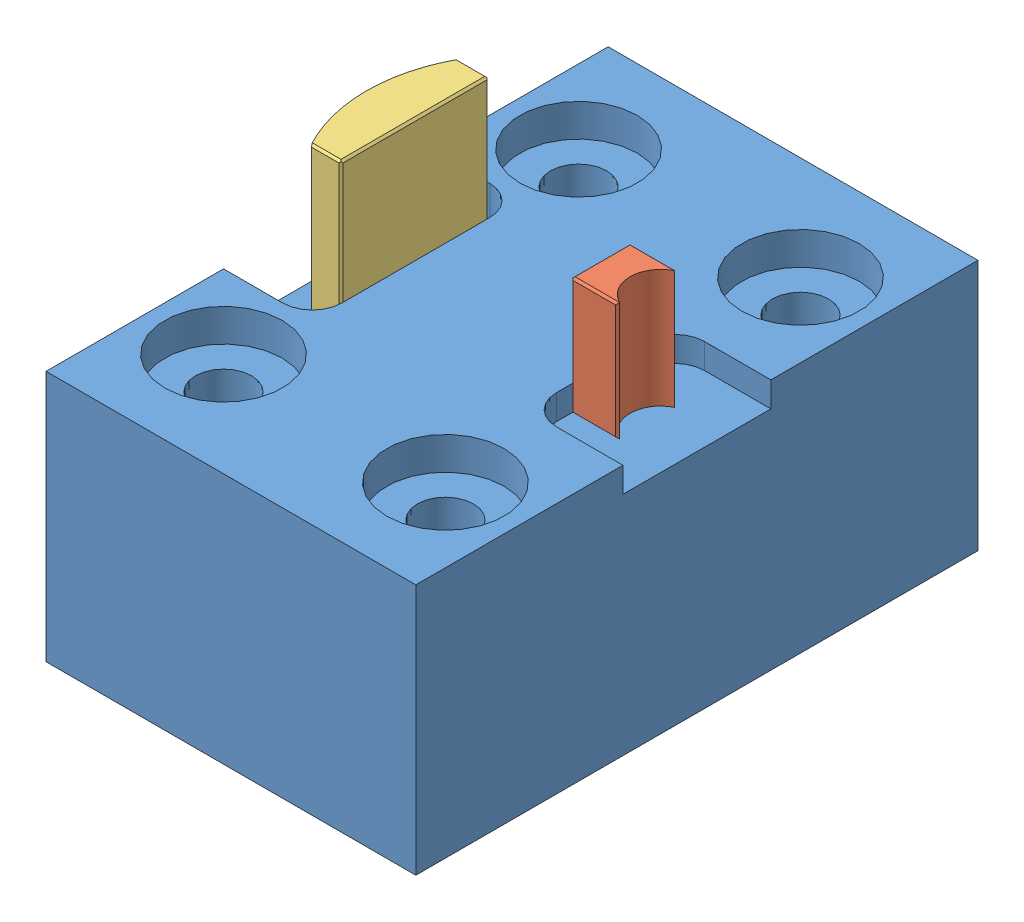
SolidWorks assembly telescope_assem, configuration Default. Lengths in mm.
Overall size (25 25.3 38).
3 component instances, 3 part files, 6 mates.
Components (placement in the parent):
- telescope_stand-1: telescope_stand [Default] at (18495.2515 8.1592 11328.0159) size (25 17 38)
- cyl_lens_concave-2: cyl_lens_concave [Default] at (21.3841 27.4592 29.848) x (0 1 0) z (1 0 0) size (8 4 3.16)
- cylindricalconvex_LJ1960L1-B-Solidworks-1: cylindricalconvex_LJ1960L1-B-Solidworks [Default] at (5.6598 27.4592 29.8856) x (0 1 0) z (-1 0 0) size (12 10 3.29)
Mates (geometry in assembly coordinates):
- Coincident2: coincident: plane of telescope_stand-1 through (18495.2515 23.4592 11328.0159) normal (0 1 0); plane of cyl_lens_concave-1 through (23.8748 28.4592 28.05) normal (0 -1 0)
- Coincident3: coincident anti-aligned: plane of telescope_stand-1 through (19.8048 -3.7676 11328.0159) normal (1 0 0); plane of cyl_lens_concave-1 through (19.8048 36.4592 30.05) normal (-1 0 0)
- Coincident6: coincident anti-aligned: plane of telescope_stand-1 through (18495.2515 23.4592 11328.0159) normal (0 1 0); plane of cyl_lens_concave-2 through (23.8748 23.4592 29.848) normal (0 -1 0)
- Coincident7: coincident anti-aligned: plane of telescope_stand-1 through (18495.2515 21.4592 11328.0159) normal (0 1 0); plane of cylindricalconvex_LJ1960L1-B-Solidworks-1 through (14.3548 21.4592 29.8856) normal (0 -1 0)
- Coincident8: coincident anti-aligned: plane of telescope_stand-1 through (7.3048 -7.0723 11328.0159) normal (-1 0 0); plane of cylindricalconvex_LJ1960L1-B-Solidworks-1 through (7.3048 33.4592 24.8856) normal (1 0 0)
- Coincident9: coincident anti-aligned: plane of telescope_stand-1 through (19.8048 -3.7676 11328.0159) normal (1 0 0); plane of cyl_lens_concave-2 through (19.8048 31.4592 31.848) normal (-1 0 0)
